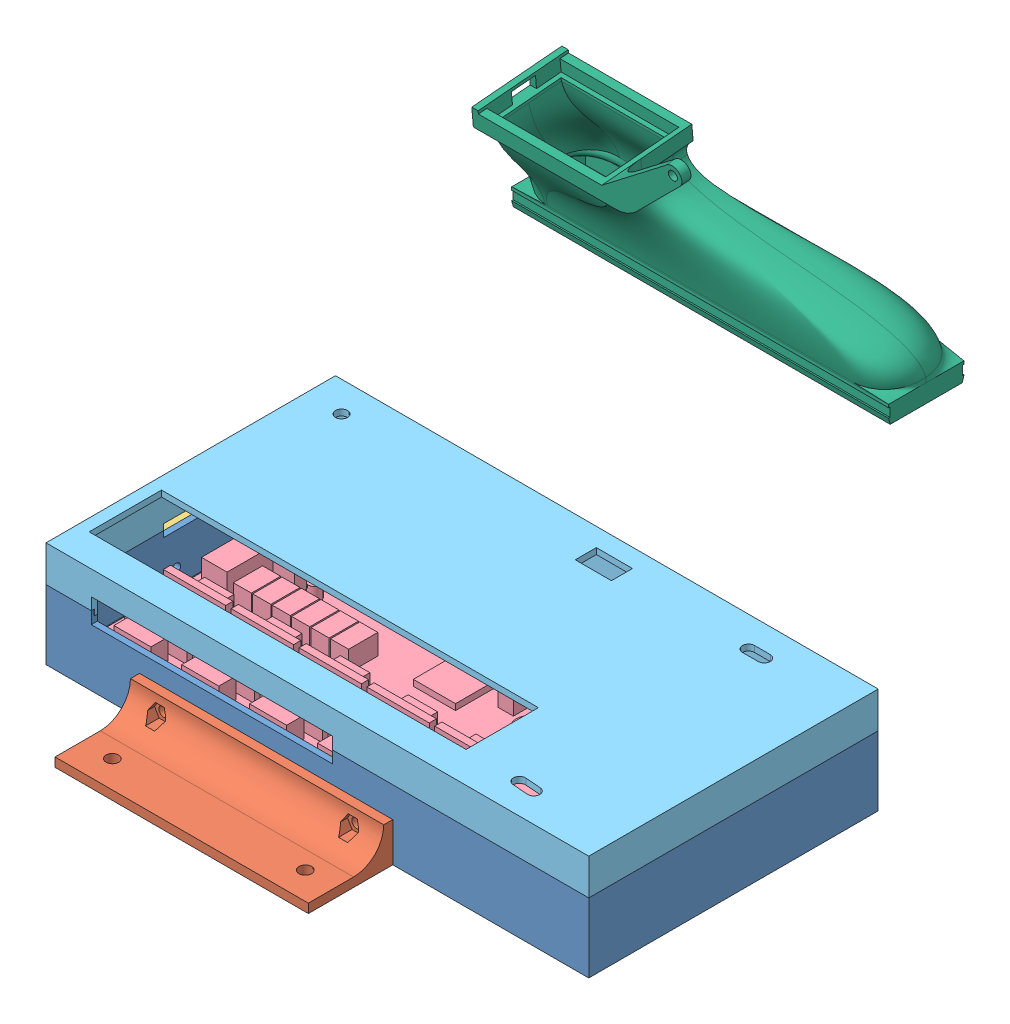
SolidWorks assembly MKSboard without ByeByeBoard, configuration Default. Lengths in mm.
Overall size (263.24 63.81 305.18).
6 component instances, 6 part files, 12 mates.
Components (placement in the parent):
- BottomWithOutByeByeBoard-1: BottomWithOutByeByeBoard [Default] at (88.2282 73.5825 127.5362) size (180 23 96)
- LongMountRigidbotOriginal-1: LongMountRigidbotOriginal [Default] at (81.7282 76.5825 189.5362) x (-1 0 0) z (0 -1 0) size (84 28 13)
- ShortMountRigidbotOriginal-1: ShortMountRigidbotOriginal [Default] at (-5.2718 76.5825 115.5362) x (0 0 -1) z (0 -1 0) size (58 28 13)
- MKS v1.3 Board-1: MKS v1.3 Board [Default] at (88.2282 80.5825 127.5362) x (-1 0 0) z (0 0 -1) size (143 20.7 84)
- LidWithOutByeByeBoard-1: LidWithOutByeByeBoard [Default] at (98.7282 106.5825 151.0362) size (180 14 130)
- RadialFanDuct-1: RadialFanDuct [Default] at (-11.5559 44.8385 -74.1904) size (126.51 63.81 58.87)
Mates (geometry in assembly coordinates):
- Coincident3: coincident anti-aligned: plane of BottomWithOutByeByeBoard-1 through (20.7282 80.5825 89.5362) normal (0 1 0); plane of MKS v1.3 Board-1 through (88.2282 80.5825 127.5362) normal (0 -1 0)
- Concentric2: concentric aligned: cylinder of BottomWithOutByeByeBoard-1 through (20.7282 76.5825 89.5362) axis (0 -1 0) radius 2; cylinder of MKS v1.3 Board-1 through (20.7282 82.2825 89.5362) axis (0 -1 0) radius 2
- Width2: width anti-aligned: plane of BottomWithOutByeByeBoard-1 through (155.7282 76.5825 87.5362) normal (0 0 1); plane of BottomWithOutByeByeBoard-1 through (155.7282 76.5825 91.5362) normal (0 0 -1); cylinder of MKS v1.3 Board-1 through (155.7282 82.2825 89.5362) axis (0 -1 0) radius 2
- Coincident4: coincident anti-aligned: plane of BottomWithOutByeByeBoard-1 through (8.7282 76.5825 79.5362) normal (-1 0 0); plane of ShortMountRigidbotOriginal-1 through (8.7282 73.5825 144.5362) normal (1 0 0)
- Concentric3: concentric anti-aligned: cylinder of BottomWithOutByeByeBoard-1 through (15.2537 81.5825 96.5362) axis (-1 0 0) radius 1.6; cylinder of ShortMountRigidbotOriginal-1 through (5.7282 81.5825 96.5362) axis (1 0 0) radius 1.6
- Concentric4: concentric anti-aligned: cylinder of BottomWithOutByeByeBoard-1 through (15.2537 81.5825 134.5362) axis (-1 0 0) radius 1.6; cylinder of ShortMountRigidbotOriginal-1 through (5.7282 81.5825 134.5362) axis (1 0 0) radius 1.6
- Coincident5: coincident anti-aligned: plane of BottomWithOutByeByeBoard-1 through (8.7282 76.5825 175.5362) normal (0 0 1); plane of LongMountRigidbotOriginal-1 through (123.7282 73.5825 175.5362) normal (0 0 -1)
- Concentric5: concentric anti-aligned: cylinder of BottomWithOutByeByeBoard-1 through (49.7282 81.5825 169.0107) axis (0 0 1) radius 1.6; cylinder of LongMountRigidbotOriginal-1 through (49.7282 81.5825 178.5362) axis (0 0 -1) radius 1.6
- Concentric6: concentric anti-aligned: cylinder of BottomWithOutByeByeBoard-1 through (113.7282 81.5825 169.0107) axis (0 0 1) radius 1.6; cylinder of LongMountRigidbotOriginal-1 through (113.7282 81.5825 178.5362) axis (0 0 -1) radius 1.6
- Coincident6: coincident anti-aligned: plane of BottomWithOutByeByeBoard-1 through (88.2282 96.5825 127.5362) normal (0 1 0); plane of LidWithOutByeByeBoard-1 through (98.7282 96.5825 151.0362) normal (0 -1 0)
- Coincident7: coincident aligned: plane of BottomWithOutByeByeBoard-1 through (188.7282 76.5825 175.5362) normal (1 0 0); plane of LidWithOutByeByeBoard-1 through (188.7282 108.5825 79.5362) normal (1 0 0)
- Coincident8: coincident aligned: plane of BottomWithOutByeByeBoard-1 through (8.7282 76.5825 175.5362) normal (0 0 1); plane of LidWithOutByeByeBoard-1 through (8.7282 108.5825 175.5362) normal (0 0 1)
